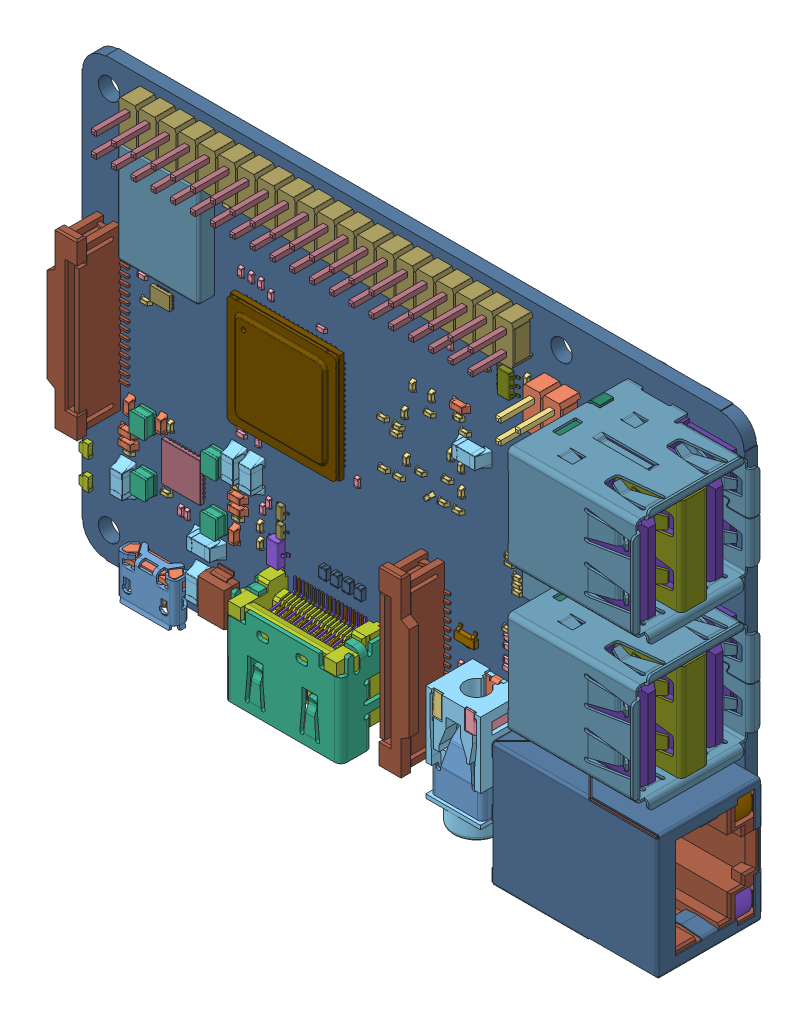
SolidWorks assembly raspberry_pi_3_b_plus.stp, configuration Default. Lengths in mm.
Overall size (87.29 58.46 20.03).
302 component instances, 65 part files, 0 mates.
Components (placement in the parent):
- micro_usb_connector v17.stp-1: micro_usb_connector v17.stp [Default] at (-31.9022 -25.6898 1.6) x (0 -1 0) z (0 0 1) size (5.84 7.77 3.4)
  - shield.stp-1: shield.stp [Default] at origin size (5.84 7.77 3.4)
  - socket_housing.stp-1: socket_housing.stp [Default] at origin size (4.25 6.85 2.15)
  - socket_plate.stp-1: socket_plate.stp [Default] at origin size (3.38 6.8 0.31)
  - terminal.stp-1: terminal.stp [Default] at origin size (3.22 0.35 1.72)
  - terminal.stp-2: terminal.stp [Default] at (0 -1.3 0) size (3.22 0.35 1.72)
  - terminal.stp-3: terminal.stp [Default] at (0 -0.65 0) size (3.22 0.35 1.72)
  - terminal.stp-4: terminal.stp [Default] at (0 0.65 0) size (3.22 0.35 1.72)
  - terminal.stp-5: terminal.stp [Default] at (0 1.3 0) size (3.22 0.35 1.72)
- sd_card_slot_molex v11.stp-1: sd_card_slot_molex v11.stp [Default] at (-35.5259 0.0195 0) x (0 1 0) z (-1 0 0) size (12 1.5 11.41)
  - housing.stp-1: housing.stp [Default] at origin size (12 1.43 11.41)
    - shell.stp-1: shell.stp [Default] at origin size (12 1.43 11.41)
  - leads.stp-1: leads.stp [Default] at origin size (10.97 1.32 10.44)
    - Component12.stp-1: Component12.stp [Default] at origin size (0.75 1.14 7.86)
    - Component13.stp-1: Component13.stp [Default] at (-1.1 0 0) size (0.75 1.16 8.16)
    - Component14.stp-1: Component14.stp [Default] at (-3.3 0 0) size (0.75 1.13 7.81)
    - Component12.stp-2: Component12.stp [Default] at (-2.2 0 0) size (0.75 1.14 7.86)
    - Component12.stp-3: Component12.stp [Default] at (-4.4 0 0) size (0.75 1.14 7.86)
    - Component12.stp-4: Component12.stp [Default] at (-6.6 0 0) size (0.75 1.14 7.86)
    - Component12.stp-5: Component12.stp [Default] at (-7.7 0 0) size (0.75 1.14 7.86)
    - Component15.stp-1: Component15.stp [Default] at origin size (1.57 1.27 4.5)
    - Component16.stp-1: Component16.stp [Default] at origin size (1.37 1.25 4.89)
    - Component14.stp-2: Component14.stp [Default] at (-5.5 0 0) size (0.75 1.13 7.81)
  - base.stp-1: base.stp [Default] at origin size (11.85 1.42 10.4)
- Pin Header 20x2 TH Pitch 2.54mm v1.stp-1: Pin Header 20x2 TH Pitch 2.54mm v1.stp [Default] at (-34.0983 24.2639 1.6) size (50.8 5.08 10)
  - spacers.stp-1: spacers.stp [Default] at origin size (50.8 5.08 2.54)
    - Component67.stp-1: Component67.stp [Default] at origin size (50.8 5.08 2.54)
  - pins.stp-1: pins.stp [Default] at origin size (48.9 3.17 10)
- USB-A-stack-1x2.stp-1: USB-A-stack-1x2.stp [Default] at (35.9589 0.6157 1.6) size (17 15.83 20.03)
  - shell_1.stp-1: shell_1.stp [Default] at origin size (17 15.83 20.03)
    - outer.stp-1: outer.stp [Default] at origin size (17 15.83 20.03)
    - back_shell.stp-1: back_shell.stp [Default] at origin size (2.8 13.7 13.5)
    - mid_cover.stp-1: mid_cover.stp [Default] at origin size (8.5 12.4 5.09)
  - Component4.stp-1: Component4.stp [Default] at origin size (16.25 12.4 15.02)
    - Component5.stp-1: Component5.stp [Default] at origin size (16.25 12.4 15.02)
  - leads_1.stp-1: leads_1.stp [Default] at origin size (14.29 8.54 16.6)
    - top_lead.stp-1: top_lead.stp [Default] at origin size (14.29 1.54 16.6)
    - top_lead.stp-2: top_lead.stp [Default] at (0 -2.5 0) size (14.29 1.54 16.6)
    - top_lead.stp-3: top_lead.stp [Default] at (0 -7 0) size (14.29 1.54 16.6)
    - top_lead.stp-4: top_lead.stp [Default] at (0 -4.5 0) size (14.29 1.54 16.6)
    - bottom_lead.stp-1: bottom_lead.stp [Default] at origin size (11.67 1.54 7.97)
    - bottom_lead.stp-2: bottom_lead.stp [Default] at (0 -7 0) size (11.67 1.54 7.97)
    - bottom_lead.stp-3: bottom_lead.stp [Default] at (0 -2.5 0) size (11.67 1.54 7.97)
    - bottom_lead.stp-4: bottom_lead.stp [Default] at (0 -4.5 0) size (11.67 1.54 7.97)
- USB-A-stack-1x2_1.stp-1: USB-A-stack-1x2_1.stp [Default] at (35.9589 19.0157 1.6) size (17 15.83 20.03)
  - shell_2.stp-1: shell_2.stp [Default] at origin size (17 15.83 20.03)
    - outer.stp-1: outer.stp [Default] at origin size (17 15.83 20.03)
    - back_shell.stp-1: back_shell.stp [Default] at origin size (2.8 13.7 13.5)
    - mid_cover.stp-1: mid_cover.stp [Default] at origin size (8.5 12.4 5.09)
  - Component4_1.stp-1: Component4_1.stp [Default] at origin size (16.25 12.4 15.02)
    - Component5.stp-1: Component5.stp [Default] at origin size (16.25 12.4 15.02)
  - leads_2.stp-1: leads_2.stp [Default] at origin size (14.29 8.54 16.6)
    - top_lead.stp-1: top_lead.stp [Default] at origin size (14.29 1.54 16.6)
    - top_lead.stp-2: top_lead.stp [Default] at (0 -2.5 0) size (14.29 1.54 16.6)
    - top_lead.stp-3: top_lead.stp [Default] at (0 -7 0) size (14.29 1.54 16.6)
    - top_lead.stp-4: top_lead.stp [Default] at (0 -4.5 0) size (14.29 1.54 16.6)
    - bottom_lead.stp-1: bottom_lead.stp [Default] at origin size (11.67 1.54 7.97)
    - bottom_lead.stp-2: bottom_lead.stp [Default] at (0 -7 0) size (11.67 1.54 7.97)
    - bottom_lead.stp-3: bottom_lead.stp [Default] at (0 -2.5 0) size (11.67 1.54 7.97)
    - bottom_lead.stp-4: bottom_lead.stp [Default] at (0 -4.5 0) size (11.67 1.54 7.97)
- Pin Header 2x2 TH Pitch 2.54mm.stp-1: Pin Header 2x2 TH Pitch 2.54mm.stp [Default] at (17.7441 18.3632 1.6) size (5.08 5.08 10)
  - spacers_1.stp-1: spacers_1.stp [Default] at origin size (5.08 5.08 2.54)
    - Component5_1.stp-1: Component5_1.stp [Default] at origin size (5.08 5.08 2.54)
  - pins_1.stp-1: pins_1.stp [Default] at origin size (3.17 3.17 10)
- EDAC_1743_RJ45_TH.stp-1: EDAC_1743_RJ45_TH.stp [Default] at (34.0212 -17.8853 1.5) x (0 1 0) z (0 0 1) size (16.2 21.37 16.96)
  - wiring.stp-1: wiring.stp [Default] at origin size (13.9 18.75 15.99)
    - rj45.stp-1: rj45.stp [Default] at origin size (13.46 13.45 4.49)
    - magnetics.stp-1: magnetics.stp [Default] at origin size (11.5 6.5 11.5)
    - leads_3.stp-1: leads_3.stp [Default] at origin size (13.9 7.95 8.72)
  - lights.stp-1: lights.stp [Default] at origin size (13.8 6.61 5.6)
    - led_org.stp-1: led_org.stp [Default] at (-5.37 0 2.2) size (3.04 5.2 4.86)
    - led_org.stp-2: led_org.stp [Default] at (5.37 0 2.2) size (3.04 5.2 4.86)
    - lights-0.stp-1: lights-0.stp [Default] at origin size (3.06 4.17 2.2)
    - lights-1.stp-1: lights-1.stp [Default] at origin size (3.06 4.17 2.2)
  - shell_3.stp-1: shell_3.stp [Default] at origin size (16.2 21.37 16.36)
  - base_1.stp-1: base_1.stp [Default] at origin size (15.6 20.75 16.5)
- qfp16_3x2mm.stp-1: qfp16_3x2mm.stp [Default] at (-32.0595 4.9149 1.6) size (2.7 1.95 0.45)
  - Component1.stp-1: Component1.stp [Default] at origin size (2.5 1.75 0.4)
  - lead.stp-1: lead.stp [Default] at origin size (2.7 1.95 0.12)
- wifi.stp-1: wifi.stp [Default] at origin size (10.5 13 2)
  - Component73.stp-1: Component73.stp [Default] at origin size (10.5 13 2)
- crystal_dfn4.stp-1: crystal_dfn4.stp [Default] at (-16.2394 -5.9832 0) x (-1 0 0) z (0 0 -1) size (3.2 2.5 0.72)
  - Component2.stp-1: Component2.stp [Default] at origin size (3.2 2.5 0.3)
  - Component3.stp-1: Component3.stp [Default] at origin size (3.2 2.5 0.4)
  - Component4_2.stp-1: Component4_2.stp [Default] at origin size (2.9 2.3 0.2)
  - Component5_2.stp-1: Component5_2.stp [Default] at origin size (2.53 1.93 0.22)
- crystal_dfn4.stp-2: crystal_dfn4.stp [Default] at (11.4677 1.4751 0) x (0 -1 0) z (0 0 -1) size (3.2 2.5 0.72)
  - Component2.stp-1: Component2.stp [Default] at origin size (3.2 2.5 0.3)
  - Component3.stp-1: Component3.stp [Default] at origin size (3.2 2.5 0.4)
  - Component4_2.stp-1: Component4_2.stp [Default] at origin size (2.9 2.3 0.2)
  - Component5_2.stp-1: Component5_2.stp [Default] at origin size (2.53 1.93 0.22)
- pj-322.stp-1: pj-322.stp [Default] at (11.1035 -22.958 1.6) x (0 1 0) z (0 0 1) size (15 7.14 8.8)
  - tip_lead.stp-1: tip_lead.stp [Default] at origin size (9.11 7.14 8.34)
  - Component2_1.stp-1: Component2_1.stp [Default] at origin size (13.26 2.5 4.34)
  - Component3_1.stp-1: Component3_1.stp [Default] at origin size (11.45 1.41 8.71)
  - Component4_3.stp-1: Component4_3.stp [Default] at origin size (8.23 1.51 8.71)
  - pj-322-2.stp-1: pj-322-2.stp [Default] at origin size (15 7 7)
- molex hdmi smt.stp-1: molex hdmi smt.stp [Default] at (-10.5578 -23.8041 1.6) size (15 12.18 8.27)
  - Component2_2.stp-1: Component2_2.stp [Default] at origin size (15 11.55 8.27)
  - molex hdmi smt-3.stp-1: molex hdmi smt-3.stp [Default] at origin size (14.9 10.35 6.23)
  - molex hdmi smt-4.stp-1: molex hdmi smt-4.stp [Default] at origin size (9.45 9.4 3.81)
  - molex hdmi smt-5.stp-1: molex hdmi smt-5.stp [Default] at origin size (8.45 9.4 3.11)
- pcb.stp-1: pcb.stp [Default] at origin size (85 56 1.6)
- te_1-1734248-5.stp-1: te_1-1734248-5.stp [Default] at (-38.8804 0.013 1.58) x (0 -1 0) z (-1 0 0) size (22.4 5.68 5.07)
- te_1-1734248-5.stp-2: te_1-1734248-5.stp [Default] at (2.6829 -16.6511 1.58) x (0 1 0) z (1 0 0) size (22.4 5.68 5.07)
- SOP-3_1.6mm.stp-1: SOP-3_1.6mm.stp [Default] at (-40.8905 -10.8155 0) x (-1 0 0) z (0 0 -1) size (1.6 1.56 0.65)
- SOP-3_1.6mm.stp-2: SOP-3_1.6mm.stp [Default] at (-40.814 -18.4594 0) x (-1 0 0) z (0 0 -1) size (1.6 1.56 0.65)
- SOP-3_1.6mm.stp-3: SOP-3_1.6mm.stp [Default] at (-16.6511 -13.2136 1.6) x (0 1 0) z (0 0 1) size (1.6 1.56 0.65)
- SOP-3_1.6mm.stp-4: SOP-3_1.6mm.stp [Default] at (-16.6511 -11.1136 1.6) x (0 1 0) z (0 0 1) size (1.6 1.56 0.65)
- qfn32_5mm.stp-1: qfn32_5mm.stp [Default] at (-29.2738 -12.9325 1.6) size (5.2 5.2 0.55)
- qfn48_9mm.stp-1: qfn48_9mm.stp [Default] at (19.0565 -0.2385 1.6) size (9 9 0.6)
- TSOP-6 2mm.stp-1: TSOP-6 2mm.stp [Default] at (14.2657 -10.6917 1.6) size (2 2.01 0.8)
- TSOP-6 3mm.stp-1: TSOP-6 3mm.stp [Default] at (12.2743 17.7497 1.6) x (0 -1 0) z (0 0 1) size (3 2.91 0.8)
- qfn80_12mm.stp-1: qfn80_12mm.stp [Default] at (0.9784 5.5219 0) x (-1 0 0) z (0 0 -1) size (12 12 0.6)
- bcm2837.stp-1: bcm2837.stp [Default] at (-15.6667 3.4614 1.6) size (14 14 1.6)
- wlbga140_5mm.stp-1: wlbga140_5mm.stp [Default] at (-30.4818 13.9472 1.6) size (4.47 5.27 0.51)
- cap0603_03.stp-1: cap0603_03.stp [Default] at (6.2017 12.0599 1.6) size (2.34 0.91 0.83)
- cap0603_03.stp-2: cap0603_03.stp [Default] at (-22.2778 -12.3124 1.6) size (2.34 0.91 0.83)
- cap0603_03.stp-3: cap0603_03.stp [Default] at (-22.2778 -13.6124 1.6) size (2.34 0.91 0.83)
- cap0603_03.stp-4: cap0603_03.stp [Default] at (-36.2901 -12.0302 1.6) size (2.34 0.91 0.83)
- cap0603_03.stp-5: cap0603_03.stp [Default] at (-36.2901 -13.3302 1.6) size (2.34 0.91 0.83)
- cap0603_03.stp-6: cap0603_03.stp [Default] at (-22.6025 -16.7071 1.6) x (0 -1 0) z (0 0 1) size (2.34 0.91 0.83)
- cap0603_03.stp-7: cap0603_03.stp [Default] at (-31.9549 -9.0739 1.6) x (0 -1 0) z (0 0 1) size (2.34 0.91 0.83)
- cap0603_03.stp-8: cap0603_03.stp [Default] at (-36.0614 -9.1191 1.6) x (0 -1 0) z (0 0 1) size (2.34 0.91 0.83)
- cap0402.stp-1: cap0402.stp [Default] at (-1.6846 0.2009 1.6) size (1.37 0.6 0.51)
- cap0402.stp-2: cap0402.stp [Default] at (-3.6165 0.1175 1.6) size (1.37 0.6 0.51)
- cap0402.stp-3: cap0402.stp [Default] at (5.921 0.2585 1.6) size (1.37 0.6 0.51)
- cap0402.stp-4: cap0402.stp [Default] at (3.9891 0.175 1.6) size (1.37 0.6 0.51)
- cap0402.stp-5: cap0402.stp [Default] at (-2.0728 4.8443 1.6) size (1.37 0.6 0.51)
- cap0402.stp-6: cap0402.stp [Default] at (-3.7336 5.7492 1.6) size (1.37 0.6 0.51)
- cap0402.stp-7: cap0402.stp [Default] at (-1.7854 5.7598 1.6) size (1.37 0.6 0.51)
- cap0402.stp-8: cap0402.stp [Default] at (1.0927 2.1177 1.6) size (1.37 0.6 0.51)
- cap0402.stp-9: cap0402.stp [Default] at (-0.6601 2.5496 1.6) x (0 -1 0) z (0 0 1) size (1.37 0.6 0.51)
- cap0402.stp-10: cap0402.stp [Default] at (-0.9045 7.6235 1.6) x (0 -1 0) z (0 0 1) size (1.37 0.6 0.51)
- cap0402.stp-11: cap0402.stp [Default] at (4.5329 2.9706 1.6) size (1.37 0.6 0.51)
- cap0402.stp-12: cap0402.stp [Default] at (6.3871 2.4516 1.6) x (0 -1 0) z (0 0 1) size (1.37 0.6 0.51)
- cap0402.stp-13: cap0402.stp [Default] at (6.3503 5.2092 1.6) x (0 -1 0) z (0 0 1) size (1.37 0.6 0.51)
- cap0402.stp-14: cap0402.stp [Default] at (4.9776 5.871 1.6) x (0 -1 0) z (0 0 1) size (1.37 0.6 0.51)
- cap0402.stp-15: cap0402.stp [Default] at (2.183 -0.0836 1.6) x (0.707107 0.707107 0) z (0 0 1) size (1.37 0.6 0.51)
- cap0402.stp-16: cap0402.stp [Default] at (2.5576 11.2194 1.6) x (0 -1 0) z (0 0 1) size (1.37 0.6 0.51)
- cap0402.stp-17: cap0402.stp [Default] at (0.1286 11.1773 1.6) x (0 -1 0) z (0 0 1) size (1.37 0.6 0.51)
- cap0402.stp-18: cap0402.stp [Default] at (2.2305 9.2075 1.6) size (1.37 0.6 0.51)
- cap0402.stp-19: cap0402.stp [Default] at (5.9654 10.5975 1.6) size (1.37 0.6 0.51)
- cap0402.stp-20: cap0402.stp [Default] at (6.7657 9.3479 1.6) size (1.37 0.6 0.51)
- cap0402.stp-21: cap0402.stp [Default] at (-23.49 19.4613 1.6) size (1.37 0.6 0.51)
- cap0402.stp-22: cap0402.stp [Default] at (-13.822 20.7849 1.6) size (1.37 0.6 0.51)
- cap0402.stp-23: cap0402.stp [Default] at (-34.1053 3.5022 1.6) size (1.37 0.6 0.51)
- cap0402.stp-24: cap0402.stp [Default] at (-31.4883 -16.4844 1.6) size (1.37 0.6 0.51)
- cap0402.stp-25: cap0402.stp [Default] at (-30.9095 -8.8802 1.6) x (0 -1 0) z (0 0 1) size (1.37 0.6 0.51)
- cap0402.stp-26: cap0402.stp [Default] at (-19.4165 -16.1422 1.6) x (0 -1 0) z (0 0 1) size (1.37 0.6 0.51)
- cap0402.stp-27: cap0402.stp [Default] at (-36.281 -14.328 1.6) size (1.37 0.6 0.51)
- cap0402.stp-28: cap0402.stp [Default] at (-19.435 -14.2136 1.6) x (0 -1 0) z (0 0 1) size (1.37 0.6 0.51)
- cap0402.stp-29: cap0402.stp [Default] at (-22.334 -14.6736 1.6) size (1.37 0.6 0.51)
- cap0402.stp-30: cap0402.stp [Default] at (21.8139 -19.5391 1.6) x (0 -1 0) z (0 0 1) size (1.37 0.6 0.51)
- cap0402.stp-31: cap0402.stp [Default] at (14.9817 -13.1373 1.6) size (1.37 0.6 0.51)
- cap0402.stp-32: cap0402.stp [Default] at (13.5717 -4.9875 1.6) size (1.37 0.6 0.51)
- cap0402.stp-33: cap0402.stp [Default] at (13.5717 -4.1816 1.6) size (1.37 0.6 0.51)
- cap0402.stp-34: cap0402.stp [Default] at (13.5938 -3.3757 1.6) size (1.37 0.6 0.51)
- cap0402.stp-35: cap0402.stp [Default] at (12.6112 -2.2828 1.6) size (1.37 0.6 0.51)
- cap0402.stp-36: cap0402.stp [Default] at (12.5671 -1.51 1.6) size (1.37 0.6 0.51)
- cap0402.stp-37: cap0402.stp [Default] at (13.5496 0.709 1.6) size (1.37 0.6 0.51)
- resistor_0402.stp-1: resistor_0402.stp [Default] at (13.5093 -0.0742 1.6) size (1.27 0.6 0.35)
- resistor_0402.stp-2: resistor_0402.stp [Default] at (13.5249 2.0611 1.6) size (1.27 0.6 0.35)
- resistor_0402.stp-3: resistor_0402.stp [Default] at (13.7425 5.6111 1.6) size (1.27 0.6 0.35)
- resistor_0402.stp-4: resistor_0402.stp [Default] at (20.9328 7.1813 1.6) x (0 -1 0) z (0 0 1) size (1.27 0.6 0.35)
- resistor_0402.stp-5: resistor_0402.stp [Default] at (21.7458 7.1931 1.6) x (0 -1 0) z (0 0 1) size (1.27 0.6 0.35)
- cap0402.stp-38: cap0402.stp [Default] at (9.6972 18.2084 1.6) x (0 -1 0) z (0 0 1) size (1.37 0.6 0.51)
- cap0402.stp-39: cap0402.stp [Default] at (14.7686 19.1245 1.6) x (0 -1 0) z (0 0 1) size (1.37 0.6 0.51)
- resistor_0402.stp-6: resistor_0402.stp [Default] at (12.3038 -10.6968 1.6) size (1.27 0.6 0.35)
- cap0402.stp-40: cap0402.stp [Default] at (12.2869 -9.7249 1.6) size (1.37 0.6 0.51)
- cap0402.stp-41: cap0402.stp [Default] at (16.278 -9.6995 1.6) size (1.37 0.6 0.51)
- resistor_0402.stp-7: resistor_0402.stp [Default] at (12.2911 -11.6977 1.6) size (1.27 0.6 0.35)
- resistor_0402.stp-8: resistor_0402.stp [Default] at (16.2822 -10.7348 1.6) size (1.27 0.6 0.35)
- resistor_0402.stp-9: resistor_0402.stp [Default] at (16.2949 -11.7484 1.6) size (1.27 0.6 0.35)
- resistor_0402.stp-10: resistor_0402.stp [Default] at (12.2922 -13.2114 1.6) size (1.27 0.6 0.35)
- resistor_0402.stp-11: resistor_0402.stp [Default] at (12.2703 -14.0987 1.6) size (1.27 0.6 0.35)
- resistor_0402.stp-12: resistor_0402.stp [Default] at (6.2757 -16.9459 1.6) x (0 1 0) z (0 0 1) size (1.27 0.6 0.35)
- resistor_0402.stp-13: resistor_0402.stp [Default] at (17.4427 -5.704 1.6) x (0 1 0) z (0 0 1) size (1.27 0.6 0.35)
- resistor_0402.stp-14: resistor_0402.stp [Default] at (18.7432 -5.7156 1.6) x (0 1 0) z (0 0 1) size (1.27 0.6 0.35)
- resistor_0402.stp-15: resistor_0402.stp [Default] at (20.5313 -5.7505 1.6) x (0 1 0) z (0 0 1) size (1.27 0.6 0.35)
- resistor_0402.stp-16: resistor_0402.stp [Default] at (21.9594 -5.7389 1.6) x (0 1 0) z (0 0 1) size (1.27 0.6 0.35)
- resistor_0402.stp-17: resistor_0402.stp [Default] at (24.5889 -0.5715 1.6) size (1.27 0.6 0.35)
- resistor_0402.stp-18: resistor_0402.stp [Default] at (24.6319 0.218 1.6) size (1.27 0.6 0.35)
- resistor_0402.stp-19: resistor_0402.stp [Default] at (14.7611 17.201 1.6) x (0 -1 0) z (0 0 1) size (1.27 0.6 0.35)
- resistor_0402.stp-20: resistor_0402.stp [Default] at (4.9081 18.0957 1.6) x (0 -1 0) z (0 0 1) size (1.27 0.6 0.35)
- resistor_0402.stp-21: resistor_0402.stp [Default] at (-7.0309 -3.1276 1.6) x (0 -1 0) z (0 0 1) size (1.27 0.6 0.35)
- resistor_0402.stp-22: resistor_0402.stp [Default] at (-19.7233 -4.9873 1.6) x (0 -1 0) z (0 0 1) size (1.27 0.6 0.35)
- resistor_0402.stp-23: resistor_0402.stp [Default] at (-21.9429 12.7546 1.6) x (0 -1 0) z (0 0 1) size (1.27 0.6 0.35)
- resistor_0402.stp-24: resistor_0402.stp [Default] at (-20.6248 12.7941 1.6) x (0 -1 0) z (0 0 1) size (1.27 0.6 0.35)
- resistor_0402.stp-25: resistor_0402.stp [Default] at (-19.3726 12.7414 1.6) x (0 -1 0) z (0 0 1) size (1.27 0.6 0.35)
- resistor_0402.stp-26: resistor_0402.stp [Default] at (-18.1072 12.0428 1.6) x (0 -1 0) z (0 0 1) size (1.27 0.6 0.35)
- resistor_0402.stp-27: resistor_0402.stp [Default] at (-11.6643 11.6022 1.6) size (1.27 0.6 0.35)
- resistor_0402.stp-28: resistor_0402.stp [Default] at (-21.8944 -4.3988 1.6) size (1.27 0.6 0.35)
- resistor_0402.stp-29: resistor_0402.stp [Default] at (-21.8845 -5.2127 1.6) size (1.27 0.6 0.35)
- resistor_0402.stp-30: resistor_0402.stp [Default] at (-34.6286 7.0225 1.6) size (1.27 0.6 0.35)
- resistor_0402.stp-31: resistor_0402.stp [Default] at (-34.6177 6.0172 1.6) size (1.27 0.6 0.35)
- resistor_0402.stp-32: resistor_0402.stp [Default] at (-23.5017 21.2684 1.6) size (1.27 0.6 0.35)
- resistor_0402.stp-33: resistor_0402.stp [Default] at (-23.4752 20.3668 1.6) size (1.27 0.6 0.35)
- resistor_0402.stp-34: resistor_0402.stp [Default] at (-27.0587 -20.8199 1.6) size (1.27 0.6 0.35)
- resistor_0402.stp-35: resistor_0402.stp [Default] at (-29.641 -17.6073 1.6) x (0 1 0) z (0 0 1) size (1.27 0.6 0.35)
- resistor_0402.stp-36: resistor_0402.stp [Default] at (-28.8414 -17.6167 1.6) x (0 1 0) z (0 0 1) size (1.27 0.6 0.35)
- resistor_0402.stp-37: resistor_0402.stp [Default] at (-19.1723 -12.1871 1.6) x (0 1 0) z (0 0 1) size (1.27 0.6 0.35)
- resistor_0402.stp-38: resistor_0402.stp [Default] at (-18.3875 -11.105 1.6) x (0 1 0) z (0 0 1) size (1.27 0.6 0.35)
- cap0402.stp-42: cap0402.stp [Default] at (-22.4123 -11.2455 1.6) size (1.37 0.6 0.51)
- resistor_0402.stp-39: resistor_0402.stp [Default] at (-1.3556 -21.6749 1.6) size (1.27 0.6 0.35)
- resistor_0402.stp-40: resistor_0402.stp [Default] at (-1.3556 -22.6419 1.6) size (1.27 0.6 0.35)
- cap1206.stp-1: cap1206.stp [Default] at (7.9842 7.8874 1.6) size (4.14 2 1.61)
- cap1206.stp-2: cap1206.stp [Default] at (-25.9964 -19.3212 1.6) size (4.14 2 1.61)
- cap1206.stp-3: cap1206.stp [Default] at (-36.5363 -17.3583 1.6) x (0 1 0) z (0 0 1) size (4.14 2 1.61)
- cap1206.stp-4: cap1206.stp [Default] at (-22.3159 -8.6166 1.6) x (0 1 0) z (0 0 1) size (4.14 2 1.61)
- cap1206.stp-5: cap1206.stp [Default] at (-20.0447 -8.6166 1.6) x (0 1 0) z (0 0 1) size (4.14 2 1.61)
- cap1206.stp-6: cap1206.stp [Default] at (-26.8904 -24.2006 1.6) x (0 1 0) z (0 0 1) size (4.14 2 1.61)
- cap1206.stp-7: cap1206.stp [Default] at (23.3268 10.3578 1.6) x (0 1 0) z (0 0 1) size (4.14 2 1.61)
- cap1206.stp-8: cap1206.stp [Default] at (23.886 19.0543 1.6) x (0 1 0) z (0 0 1) size (4.14 2 1.61)
- cap1206.stp-9: cap1206.stp [Default] at (25.6036 -6.141 1.6) x (0 1 0) z (0 0 1) size (4.14 2 1.61)
- cap1206.stp-10: cap1206.stp [Default] at (16.4512 -16.6927 1.6) x (0 1 0) z (0 0 1) size (4.14 2 1.61)
- cap1206.stp-11: cap1206.stp [Default] at (17.7022 -20.3318 1.6) size (4.14 2 1.61)
- cap0603_03.stp-9: cap0603_03.stp [Default] at (-16.8344 0.8188 -0.0007) x (-1 0 0) z (0 0 -1) size (2.34 0.91 0.83)
- cap0603_03.stp-10: cap0603_03.stp [Default] at (-16.6946 6.8765 -0.0007) x (-1 0 0) z (0 0 -1) size (2.34 0.91 0.83)
- cap0603_03.stp-11: cap0603_03.stp [Default] at (-40.1331 -7.592 -0.0007) x (-1 0 0) z (0 0 -1) size (2.34 0.91 0.83)
- cap0603_03.stp-12: cap0603_03.stp [Default] at (13.801 -4.8435 -0.0007) x (-1 0 0) z (0 0 -1) size (2.34 0.91 0.83)
- cap0603_03.stp-13: cap0603_03.stp [Default] at (22.8947 7.0224 -0.0007) x (-1 0 0) z (0 0 -1) size (2.34 0.91 0.83)
- cap0603_03.stp-14: cap0603_03.stp [Default] at (21.8412 4.9066 -0.0007) x (0 1 0) z (0 0 -1) size (2.34 0.91 0.83)
- cap0603_03.stp-15: cap0603_03.stp [Default] at (-11.6562 12.1885 -0.0007) x (0 1 0) z (0 0 -1) size (2.34 0.91 0.83)
- resistor_0402.stp-41: resistor_0402.stp [Default] at (-40.4693 -16.2711 0) x (0 1 0) z (0 0 -1) size (1.27 0.6 0.35)
- resistor_0402.stp-42: resistor_0402.stp [Default] at (-38.4065 -15.2729 0) x (0 1 0) z (0 0 -1) size (1.27 0.6 0.35)
- resistor_0402.stp-43: resistor_0402.stp [Default] at (-40.3279 -13.3183 0) x (0 1 0) z (0 0 -1) size (1.27 0.6 0.35)
- resistor_0402.stp-44: resistor_0402.stp [Default] at (-41.509 -13.3515 0) x (0 1 0) z (0 0 -1) size (1.27 0.6 0.35)
- resistor_0402.stp-45: resistor_0402.stp [Default] at (-33.0196 -7.5021 0) x (0 1 0) z (0 0 -1) size (1.27 0.6 0.35)
- resistor_0402.stp-46: resistor_0402.stp [Default] at (-26.8703 5.0577 0) x (-1 0 0) z (0 0 -1) size (1.27 0.6 0.35)
- resistor_0402.stp-47: resistor_0402.stp [Default] at (-22.4565 -0.6922 0) x (-1 0 0) z (0 0 -1) size (1.27 0.6 0.35)
- resistor_0402.stp-48: resistor_0402.stp [Default] at (-23.3861 9.2989 0) x (-0.707107 -0.707107 0) z (0 0 -1) size (1.27 0.6 0.35)
- resistor_0402.stp-49: resistor_0402.stp [Default] at (-9.0472 -4.0009 0) x (-1 0 0) z (0 0 -1) size (1.27 0.6 0.35)
- resistor_0402.stp-50: resistor_0402.stp [Default] at (1.7048 -1.558 0) x (-1 0 0) z (0 0 -1) size (1.27 0.6 0.35)
- resistor_0402.stp-51: resistor_0402.stp [Default] at (7.8768 5.1135 0) x (0 -1 0) z (0 0 -1) size (1.27 0.6 0.35)
- resistor_0402.stp-52: resistor_0402.stp [Default] at (16.9042 9.1312 0) x (0 -1 0) z (0 0 -1) size (1.27 0.6 0.35)
- resistor_0402.stp-53: resistor_0402.stp [Default] at (17.8087 9.1423 0) x (0 -1 0) z (0 0 -1) size (1.27 0.6 0.35)
- resistor_0402.stp-54: resistor_0402.stp [Default] at (20.8307 4.3775 0) x (0 -1 0) z (0 0 -1) size (1.27 0.6 0.35)
- resistor_0402.stp-55: resistor_0402.stp [Default] at (18.8675 -5.4278 0) x (0 -1 0) z (0 0 -1) size (1.27 0.6 0.35)
- resistor_0402.stp-56: resistor_0402.stp [Default] at (23.2421 -0.9015 0) x (-1 0 0) z (0 0 -1) size (1.27 0.6 0.35)
- resistor_0402.stp-57: resistor_0402.stp [Default] at (23.2421 0.6867 0) x (-1 0 0) z (0 0 -1) size (1.27 0.6 0.35)
- cap0402.stp-43: cap0402.stp [Default] at (-20.9328 -4.704 0) x (1 0 0) z (0 0 -1) size (1.37 0.6 0.51)
- cap0402.stp-44: cap0402.stp [Default] at (-20.4676 -3.7177 0) x (1 0 0) z (0 0 -1) size (1.37 0.6 0.51)
- cap0402.stp-45: cap0402.stp [Default] at (-20.1419 -2.7314 0) x (1 0 0) z (0 0 -1) size (1.37 0.6 0.51)
- cap0402.stp-46: cap0402.stp [Default] at (-20.5327 -1.438 0) x (1 0 0) z (0 0 -1) size (1.37 0.6 0.51)
- ind2520.stp-1: ind2520.stp [Default] at (-33.8028 -16.3221 1.6) x (0 1 0) z (0 0 1) size (2.5 2 1.53)
- ind2520.stp-2: ind2520.stp [Default] at (-33.9058 -9.5866 1.6) x (0 1 0) z (0 0 1) size (2.5 2 1.53)
- ind2520.stp-3: ind2520.stp [Default] at (-24.8087 -16.2044 1.6) x (0 1 0) z (0 0 1) size (2.5 2 1.53)
- ind2520.stp-4: ind2520.stp [Default] at (-24.7831 -9.5014 1.6) x (0 1 0) z (0 0 1) size (2.5 2 1.53)
- ledra_0603.stp-1: ledra_0603.stp [Default] at (-41.4207 -16.546 1.6) size (1.2 1.7 0.6)
- ledra_0603.stp-2: ledra_0603.stp [Default] at (-41.4207 -20.2157 1.6) size (1.2 1.7 0.6)
- SOP-3.stp-1: SOP-3.stp [Default] at (-17.0907 -15.6679 1.6) x (0 1 0) z (0 0 1) size (3 2.71 1.05)
- SOP-3 2.5mm.stp-1: SOP-3 2.5mm.stp [Default] at (7.1392 -13.3247 1.6) size (2.6 2.21 0.65)
- capar2_1013.stp-1: capar2_1013.stp [Default] at (-11.0324 -15.0395 1.6) x (0 1 0) z (0 0 1) size (1.47 1 0.66)
- capar2_1013.stp-2: capar2_1013.stp [Default] at (-9.5324 -15.0395 1.6) x (0 1 0) z (0 0 1) size (1.47 1 0.66)
- capar2_1013.stp-3: capar2_1013.stp [Default] at (-8.0324 -15.0395 1.6) x (0 1 0) z (0 0 1) size (1.47 1 0.66)
- capar2_1013.stp-4: capar2_1013.stp [Default] at (-6.5324 -15.0395 1.6) x (0 1 0) z (0 0 1) size (1.47 1 0.66)
- TSOP-2 4mm.stp-1: TSOP-2 4mm.stp [Default] at (-23.9074 -24.0113 1.6) size (3.5 5.91 2.05)
- cap0402.stp-47: cap0402.stp [Default] at (-22.0963 -2.7373 0) x (1 0 0) z (0 0 -1) size (1.37 0.6 0.51)
- cap0402.stp-48: cap0402.stp [Default] at (-19.3215 0.4779 0) x (1 0 0) z (0 0 -1) size (1.37 0.6 0.51)
- cap0402.stp-49: cap0402.stp [Default] at (-15.3356 -0.1607 0) x (1 0 0) z (0 0 -1) size (1.37 0.6 0.51)
- cap0402.stp-50: cap0402.stp [Default] at (-11.702 -0.7333 0) x (1 0 0) z (0 0 -1) size (1.37 0.6 0.51)
- cap0402.stp-51: cap0402.stp [Default] at (-8.9713 -5.0055 0) x (1 0 0) z (0 0 -1) size (1.37 0.6 0.51)
- cap0402.stp-52: cap0402.stp [Default] at (-15.5999 -3.3979 0) x (1 0 0) z (0 0 -1) size (1.37 0.6 0.51)
- cap0402.stp-53: cap0402.stp [Default] at (-21.6338 1.8653 0) x (1 0 0) z (0 0 -1) size (1.37 0.6 0.51)
- cap0402.stp-54: cap0402.stp [Default] at (-20.9732 3.1205 0) x (1 0 0) z (0 0 -1) size (1.37 0.6 0.51)
- cap0402.stp-55: cap0402.stp [Default] at (-16.8111 2.548 0) x (1 0 0) z (0 0 -1) size (1.37 0.6 0.51)
- cap0402.stp-56: cap0402.stp [Default] at (-12.9132 3.1866 0) x (1 0 0) z (0 0 -1) size (1.37 0.6 0.51)
- cap0402.stp-57: cap0402.stp [Default] at (-20.5107 5.1465 0) x (1 0 0) z (0 0 -1) size (1.37 0.6 0.51)
- cap0402.stp-58: cap0402.stp [Default] at (-18.6168 5.7411 0) x (1 0 0) z (0 0 -1) size (1.37 0.6 0.51)
- cap0402.stp-59: cap0402.stp [Default] at (-12.1204 6.4018 0) x (1 0 0) z (0 0 -1) size (1.37 0.6 0.51)
- cap0402.stp-60: cap0402.stp [Default] at (-20.4887 6.4678 0) x (1 0 0) z (0 0 -1) size (1.37 0.6 0.51)
- cap0402.stp-61: cap0402.stp [Default] at (-18.1783 9.7527 0) x (1 0 0) z (0 0 -1) size (1.37 0.6 0.51)
- cap0402.stp-62: cap0402.stp [Default] at (11.5736 3.8589 0) x (1 0 0) z (0 0 -1) size (1.37 0.6 0.51)
- cap0402.stp-63: cap0402.stp [Default] at (-19.3344 8.2178 0) x (0.707107 -0.707107 0) z (0 0 -1) size (1.37 0.6 0.51)
- cap0402.stp-64: cap0402.stp [Default] at (-6.2738 10.481 0) x (0.707107 -0.707107 0) z (0 0 -1) size (1.37 0.6 0.51)
- cap0402.stp-65: cap0402.stp [Default] at (-17.4936 8.4844 0) x (0 -1 0) z (0 0 -1) size (1.37 0.6 0.51)
- cap0402.stp-66: cap0402.stp [Default] at (-14.4924 9.289 0) x (0 -1 0) z (0 0 -1) size (1.37 0.6 0.51)
- cap0402.stp-67: cap0402.stp [Default] at (-13.2739 7.7737 0) x (0 -1 0) z (0 0 -1) size (1.37 0.6 0.51)
- cap0402.stp-68: cap0402.stp [Default] at (-12.604 9.6696 0) x (0 -1 0) z (0 0 -1) size (1.37 0.6 0.51)
- cap0402.stp-69: cap0402.stp [Default] at (-13.236 4.9424 0) x (0 -1 0) z (0 0 -1) size (1.37 0.6 0.51)
- cap0402.stp-70: cap0402.stp [Default] at (-18.4815 -0.9351 0) x (0 -1 0) z (0 0 -1) size (1.37 0.6 0.51)
- cap0402.stp-71: cap0402.stp [Default] at (-14.5884 2.4903 0) x (0 -1 0) z (0 0 -1) size (1.37 0.6 0.51)
- cap0402.stp-72: cap0402.stp [Default] at (-16.5097 -0.9351 0) x (0 -1 0) z (0 0 -1) size (1.37 0.6 0.51)
- cap0402.stp-73: cap0402.stp [Default] at (-15.1951 -1.9084 0) x (0 -1 0) z (0 0 -1) size (1.37 0.6 0.51)
- cap0402.stp-74: cap0402.stp [Default] at (-12.5787 -2.0474 0) x (0 -1 0) z (0 0 -1) size (1.37 0.6 0.51)
- cap0402.stp-75: cap0402.stp [Default] at (-6.04 0.8805 0) x (-0.707107 -0.707107 0) z (0 0 -1) size (1.37 0.6 0.51)
- cap0402.stp-76: cap0402.stp [Default] at (-18.4562 -3.3619 0) x (0 -1 0) z (0 0 -1) size (1.37 0.6 0.51)
- cap0402.stp-77: cap0402.stp [Default] at (-19.5306 -5.6624 0) x (0 -1 0) z (0 0 -1) size (1.37 0.6 0.51)
- cap0402.stp-78: cap0402.stp [Default] at (-18.6837 -5.7003 0) x (0 -1 0) z (0 0 -1) size (1.37 0.6 0.51)
- cap0402.stp-79: cap0402.stp [Default] at (-13.8427 -6.3828 0) x (0 -1 0) z (0 0 -1) size (1.37 0.6 0.51)
- cap0402.stp-80: cap0402.stp [Default] at (-26.961 -15.7507 0) x (0 -1 0) z (0 0 -1) size (1.37 0.6 0.51)
- cap0402.stp-81: cap0402.stp [Default] at (16.475 4.4456 0) x (0 -1 0) z (0 0 -1) size (1.37 0.6 0.51)
- cap0402.stp-82: cap0402.stp [Default] at (16.7816 1.9239 0) x (0 -1 0) z (0 0 -1) size (1.37 0.6 0.51)
- cap0402.stp-83: cap0402.stp [Default] at (18.0539 1.8856 0) x (0 -1 0) z (0 0 -1) size (1.37 0.6 0.51)
- cap0402.stp-84: cap0402.stp [Default] at (18.8714 1.8856 0) x (0 -1 0) z (0 0 -1) size (1.37 0.6 0.51)
- cap0402.stp-85: cap0402.stp [Default] at (21.3016 1.0902 0) x (0 -1 0) z (0 0 -1) size (1.37 0.6 0.51)
- cap0402.stp-86: cap0402.stp [Default] at (20.7714 -1.1412 0) x (0 -1 0) z (0 0 -1) size (1.37 0.6 0.51)
- cap0402.stp-87: cap0402.stp [Default] at (15.6457 -5.4269 0) x (0 -1 0) z (0 0 -1) size (1.37 0.6 0.51)
- cap0402.stp-88: cap0402.stp [Default] at (16.4457 -5.4269 0) x (0 -1 0) z (0 0 -1) size (1.37 0.6 0.51)
- cap0402.stp-89: cap0402.stp [Default] at (17.2457 -5.4269 0) x (0 -1 0) z (0 0 -1) size (1.37 0.6 0.51)
- cap0402.stp-90: cap0402.stp [Default] at (23.2344 -3.9236 0) x (1 0 0) z (0 0 -1) size (1.37 0.6 0.51)
